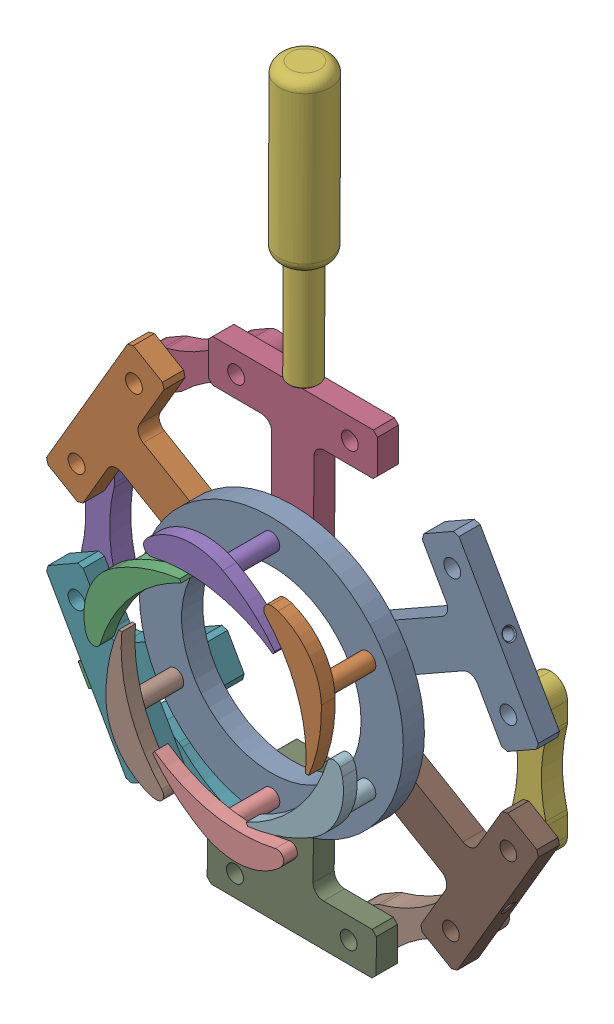
SolidWorks assembly GV000 Final, configuration Default. Lengths in mm.
Overall size (234.91 356.1 61.3).
26 component instances, 6 part files, 21 mates.
Components (placement in the parent):
- GV006-1: GV006 [Default] at origin size (125 125 10)
- GV Sub Assembly-1: GV Sub Assembly [Default] at (-45.4663 26.25 -10) x (0.504544 0.863386 0) z (0 0 1) size (80 78.32 47.3)
  - GV001-1: GV001 [Default] at origin size (80 70 10)
  - GV005-1: GV005 [Default] at (0 0 35.8) size (62.16 25.89 47.3)
- GV Sub Assembly-2: GV Sub Assembly [Default] at (0 52.5 -10) x (0.999989 -0.004765 0) z (0 0 1) size (80 78.32 47.3)
  - GV001-1: GV001 [Default] at origin size (80 70 10)
  - GV005-1: GV005 [Default] at (0 0 35.8) size (62.16 25.89 47.3)
- GV002-1: GV002 [Default] at (0.5241 162.4988 -10) x (0.004765 0.999989 0) z (0.545219 -0.002598 -0.83829) size (142 24 24)
- GV Sub Assembly-3: GV Sub Assembly [Default] at (-45.4663 -26.25 -10) x (-0.495017 0.868883 0) z (0 0 1) size (80 78.32 47.3)
  - GV001-1: GV001 [Default] at origin size (80 70 10)
  - GV005-1: GV005 [Default] at (0 0 35.8) size (62.16 25.89 47.3)
- GV Sub Assembly-4: GV Sub Assembly [Default] at (0 -52.5 -10) x (-0.999981 0.006234 0) z (0 0 1) size (80 78.32 47.3)
  - GV001-1: GV001 [Default] at origin size (80 70 10)
  - GV005-1: GV005 [Default] at (0 0 35.8) size (62.16 25.89 47.3)
- GV Sub Assembly-5: GV Sub Assembly [Default] at (45.4663 -26.25 -10) x (-0.505811 -0.862644 0) z (0 0 1) size (80 78.32 47.3)
  - GV001-1: GV001 [Default] at origin size (80 70 10)
  - GV005-1: GV005 [Default] at (0 0 35.8) size (62.16 25.89 47.3)
- GV Sub Assembly-8: GV Sub Assembly [Default] at (45.4663 26.25 -10) x (0.493741 -0.869609 0) z (0 0 1) size (80 78.32 47.3)
  - GV001-1: GV001 [Default] at origin size (80 70 10)
  - GV005-1: GV005 [Default] at (0 0 35.8) size (62.16 25.89 47.3)
- GV004-1: GV004 [Default] at (-97.5993 -55.951 -10) x (-0.495017 0.868883 0) z (-0.868883 -0.495017 0) size (10 24 20.8)
- modified link-1: modified link [Default] at (-50.8624 88.6649 -20) x (0.499738 -0.866177 0) z (0 0 1) size (16 71.6 10)
- modified link-2: modified link [Default] at (-102.2172 0.3121 -20) x (1 -0.000333 0) z (0 0 1) size (16 71.6 10)
- modified link-3: modified link [Default] at (102.2166 -0.3954 -20) x (-1 0.000421 0) z (0 0 1) size (16 71.6 10)
- modified link-4: modified link [Default] at (-51.4028 -88.3526 -20) x (0.500314 0.865844 0) z (0 0 1) size (16 71.6 10)
- modified link-5: modified link [Default] at (50.79 -88.7062 -20) x (-0.499661 0.866221 0) z (0 0 1) size (16 71.6 10)
Mates (geometry in assembly coordinates):
- Hinge1: hinge anti-aligned: cylinder of GV Sub Assembly-2/GV001-1 through (0 52.5 -15) axis (0 0 1) radius 4; circle of GV006-1; plane of GV Sub Assembly-2/GV001-1 through (0 52.5 -5) normal (0 0 1); plane of GV006-1 through (0 0 -5) normal (0 0 -1)
- Hinge2: hinge anti-aligned: circle of GV Sub Assembly-1/GV001-1; circle of GV006-1; plane of GV Sub Assembly-1/GV001-1 through (-45.4663 26.25 -5) normal (0 0 1); plane of GV006-1 through (0 0 -5) normal (0 0 -1)
- Concentric1: concentric aligned: line of GV Sub Assembly-2/GV001-1 through (7.5753 112.0199 -10) axis (0.126256 0.991998 0); line of GV002-1 through (6.1234 100.6119 -10) axis (0.126256 0.991998 0)
- Hinge7: hinge anti-aligned: cylinder of GV Sub Assembly-3/GV001-1 through (-45.4663 -26.25 -15) axis (0 0 1) radius 4; cylinder of GV006-1 through (-45.4663 -26.25 -5) axis (0 0 1) radius 4; plane of GV Sub Assembly-3/GV001-1 through (-45.4663 -26.25 -5) normal (0 0 1); plane of GV006-1 through (0 0 -5) normal (0 0 -1)
- Hinge13: hinge anti-aligned: cylinder of GV Sub Assembly-4/GV001-1 through (0 -52.5 -15) axis (0 0 1) radius 4; cylinder of GV006-1 through (0 -52.5 -5) axis (0 0 1) radius 4; plane of GV Sub Assembly-4/GV001-1 through (0 -52.5 -5) normal (0 0 1); plane of GV006-1 through (0 0 -5) normal (0 0 -1)
- Hinge17: hinge anti-aligned: cylinder of GV Sub Assembly-5/GV001-1 through (45.4663 -26.25 -15) axis (0 0 1) radius 4; cylinder of GV006-1 through (45.4663 -26.25 -5) axis (0 0 1) radius 4; plane of GV Sub Assembly-5/GV001-1 through (45.4663 -26.25 -5) normal (0 0 1); plane of GV006-1 through (0 0 -5) normal (0 0 -1)
- Hinge20: hinge anti-aligned: cylinder of GV Sub Assembly-8/GV001-1 through (45.4663 26.25 -15) axis (0 0 1) radius 4; cylinder of GV006-1 through (45.4663 26.25 -5) axis (0 0 1) radius 4; plane of GV Sub Assembly-8/GV001-1 through (45.4663 26.25 -5) normal (0 0 1); plane of GV006-1 through (0 0 -5) normal (0 0 -1)
- Coincident1: coincident anti-aligned: plane of GV Sub Assembly-2/GV001-1; plane of GV002-1
- Concentric2: concentric aligned: cylinder of GV Sub Assembly-3/GV001-1 through (-100.8015 -49.4452 -10) axis (-0.922253 -0.386586 0) radius 2.5; cylinder of GV004-1 through (-99.3259 -48.8266 -10) axis (-0.922253 -0.386586 0) radius 3.5
- Coincident4: coincident anti-aligned: plane of GV Sub Assembly-3/GV001-1; plane of GV004-1
- Coincident5: coincident anti-aligned: plane of GV Sub Assembly-3/GV001-1 through (-45.4663 -26.25 -15) normal (0 0 -1); plane of GV004-1 through (-101.2589 -44.2154 -15) normal (0 0 1)
- Hinge21: hinge anti-aligned: cylinder of modified link-1 through (-20.3719 105.4962 -25) axis (0 0 1) radius 4; cylinder of modified link-1 through (-20.3719 105.4962 -15) axis (0 0 1) radius 4; plane of GV Sub Assembly-2/GV001-1 through (-44.6755 91.7128 -15) normal (0 0 1); plane of GV Sub Assembly-2/GV001-1 through (0 52.5 -15) normal (0 0 -1)
- Hinge22: hinge anti-aligned: cylinder of modified link-1 through (-68.979 77.9294 -25) axis (0 0 1) radius 4; cylinder of GV Sub Assembly-1/GV001-1 through (-68.979 77.9294 -15) axis (0 0 1) radius 4; plane of GV Sub Assembly-1/GV001-1 through (-45.4663 26.25 -15) normal (0 0 -1); plane of modified link-1 through (-44.6755 91.7128 -15) normal (0 0 1)
- Hinge23: hinge anti-aligned: cylinder of GV Sub Assembly-1/GV001-1 through (-101.548 35.1077 -15) axis (0 0 1) radius 4; cylinder of modified link-2 through (-101.548 35.1077 -25) axis (0 0 1) radius 4; plane of modified link-2 through (-101.7631 7.1685 -15) normal (0 0 1); plane of GV Sub Assembly-1/GV001-1 through (-45.4663 26.25 -15) normal (0 0 -1)
- Hinge24: hinge anti-aligned: cylinder of modified link-2 through (-101.9782 -20.7707 -25) axis (0 0 1) radius 4; cylinder of modified link-2 through (-101.9782 -20.7707 -15) axis (0 0 1) radius 4; plane of GV Sub Assembly-3/GV001-1 through (-101.7631 7.1685 -15) normal (0 0 1); plane of GV Sub Assembly-3/GV001-1 through (-45.4663 -26.25 -15) normal (0 0 -1)
- Hinge25: hinge anti-aligned: cylinder of GV Sub Assembly-3/GV001-1 through (-81.1798 -70.3879 -15) axis (0 0 1) radius 4; cylinder of GV Sub Assembly-3/GV001-1 through (-81.1798 -70.3879 -25) axis (0 0 1) radius 4; plane of modified link-4 through (-45.4663 -26.25 -15) normal (0 0 -1); plane of modified link-4 through (-57.0914 -84.5438 -15) normal (0 0 1)
- Hinge26: hinge anti-aligned: cylinder of modified link-4 through (-33.0029 -98.6997 -25) axis (0 0 1) radius 4; cylinder of modified link-4 through (-33.0029 -98.6997 -15) axis (0 0 1) radius 4; plane of GV Sub Assembly-4/GV001-1 through (-57.0914 -84.5438 -15) normal (0 0 1); plane of GV Sub Assembly-4/GV001-1 through (0 -52.5 -15) normal (0 0 -1)
- Hinge27: hinge anti-aligned: cylinder of modified link-5 through (20.3658 -105.4985 -25) axis (0 0 1) radius 4; cylinder of modified link-5 through (20.3658 -105.4985 -15) axis (0 0 1) radius 4; plane of GV Sub Assembly-4/GV001-1 through (44.6694 -91.7153 -15) normal (0 0 1); plane of GV Sub Assembly-4/GV001-1 through (0 -52.5 -15) normal (0 0 -1)
- Hinge28: hinge anti-aligned: cylinder of modified link-5 through (68.973 -77.9322 -25) axis (0 0 1) radius 4; cylinder of modified link-5 through (68.973 -77.9322 -15) axis (0 0 1) radius 4; plane of GV Sub Assembly-5/GV001-1 through (44.6694 -91.7153 -15) normal (0 0 1); plane of GV Sub Assembly-5/GV001-1 through (45.4663 -26.25 -15) normal (0 0 -1)
- Hinge29: hinge anti-aligned: cylinder of modified link-3 through (101.547 -35.1142 -25) axis (0 0 1) radius 4; cylinder of modified link-3 through (101.547 -35.1142 -15) axis (0 0 1) radius 4; plane of GV Sub Assembly-5/GV001-1 through (101.7622 -7.175 -15) normal (0 0 1); plane of GV Sub Assembly-5/GV001-1 through (45.4663 -26.25 -15) normal (0 0 -1)
- Hinge31: hinge anti-aligned: cylinder of modified link-3 through (101.9775 20.7642 -25) axis (0 0 1) radius 4; cylinder of modified link-3 through (101.9775 20.7642 -15) axis (0 0 1) radius 4; plane of GV Sub Assembly-8/GV001-1 through (101.7622 -7.175 -15) normal (0 0 1); plane of GV Sub Assembly-8/GV001-1 through (45.4663 26.25 -15) normal (0 0 -1)
